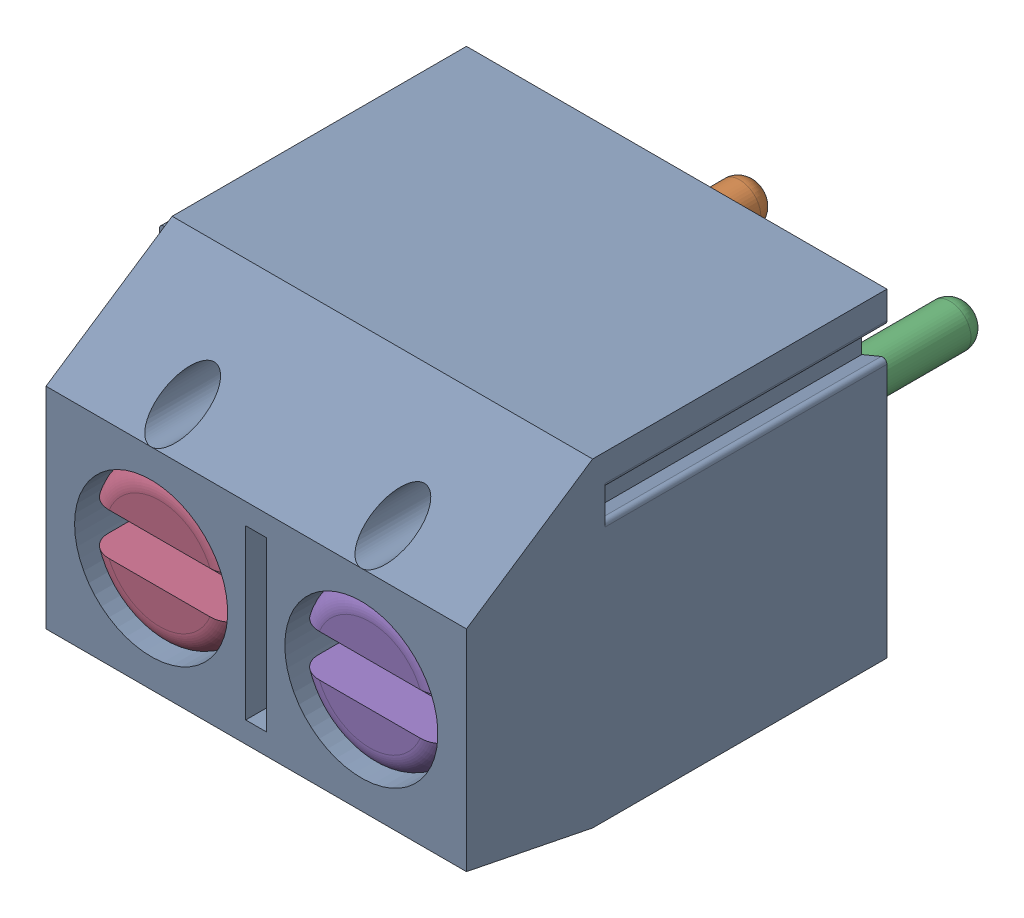
SolidWorks assembly DG301-5.0-02 (OPTION 1)-2, configuration Default. Lengths in mm.
Overall size (10.6 7.6 14.4).
7 component instances, 4 part files, 0 mates.
Components (placement in the parent):
- DG301-5.0-02-body-1: DG301-5.0-02-body [Default] at origin size (10.6 7.6 10)
- DG301-5.0-pin-1: DG301-5.0-pin [Default] at (0 0.5 2.85) size (3.9 4 9.9)
- DG301-5.0-pin-2: DG301-5.0-pin [Default] at (5 0.5 2.85) size (3.9 4 9.9)
- DG301-5.0-screw-1: DG301-5.0-screw [Default] at (0 0 4) size (3.6 3.6 5.84)
- DG301-5.0-screw-2: DG301-5.0-screw [Default] at (5 0 4) size (3.6 3.6 5.84)
- DG301-5.0-wire_prot-1: DG301-5.0-wire_prot [Default] at (5 0 5.5) size (3.9 5.45 2.85)
- DG301-5.0-wire_prot-2: DG301-5.0-wire_prot [Default] at (0 0 5.5) size (3.9 5.45 2.85)
